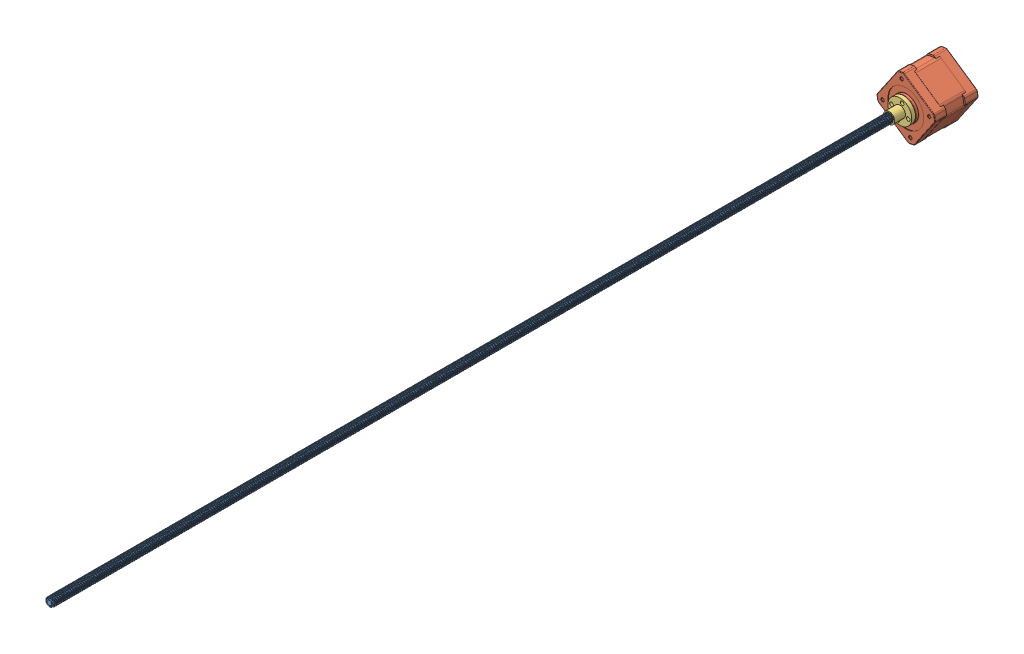
SolidWorks assembly nema 17 s trapezovou tyčí, configuration Výchozí. Lengths in mm.
Overall size (63.91 66.27 836.32).
3 component instances, 3 part files, 3 mates.
Components (placement in the parent):
- trapezová tyč-1: trapezová tyč [Valor predeterminado] at origin size (10 10 810.12)
- Nema17 bez tyče-1: Nema17 bez tyče [Výchozí] at (0 0 -431.2605) x (0.825081 -0.565014 0) z (-0.565014 -0.825081 0) size (42.3 62.01 51.35)
- t8 debil-3: t8 debil [Výchozí] at (-12.4861 -27.704 -384.4664) x (0.933013 -0.25 -0.258819) z (0.258819 0.965926 0) size (22.16 17.25 22)
Mates (geometry in assembly coordinates):
- Soustředná1: concentric anti-aligned: circle of trapezová tyč-1; circle of Nema17 bez tyče-1
- Sjednocená1: coincident anti-aligned: plane of Nema17 bez tyče-1 through (0 0 -389.2605) normal (0 0 1); plane of t8 debil-3 through (-0.0564 0.0238 -389.2605) normal (0 0 -1)
- Sjednocená2: coincident aligned: plane of Nema17 bez tyče-1 through (0 0 -389.2605) normal (0 0 1); circle of t8 debil-3
